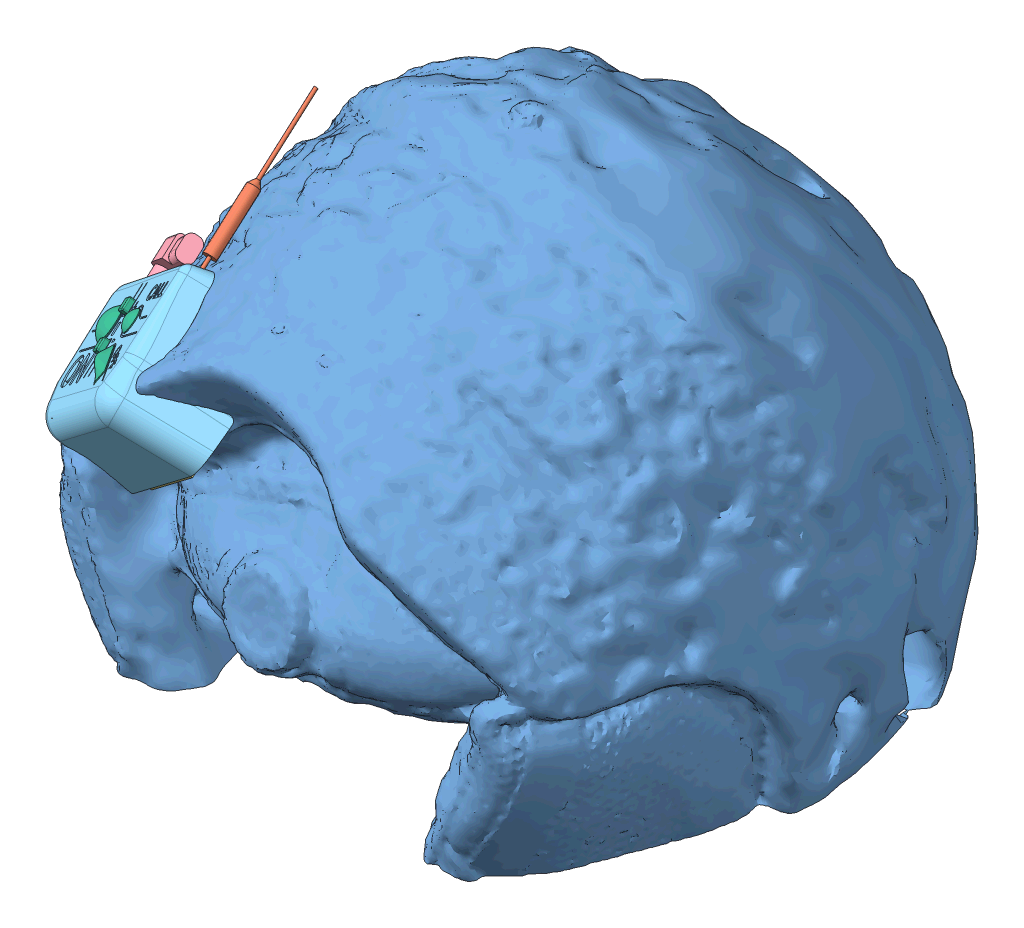
SolidWorks assembly Assem1, configuration Default. Lengths in mm.
Overall size (730.14 357.29 573.31).
6 component instances, 6 part files, 10 mates.
Components (placement in the parent):
- shield helmet-1: shield helmet [Default] at origin size (730.14 357.29 573.31)
- pcb-1: pcb [Default] at (-96.8762 130.6097 141.2413) x (-0.706127 -0.618862 -0.344083) z (0.702545 -0.551659 -0.449559) size (69.38 94.69 8.1)
- lipo850mAh30x50x6-1: lipo850mAh30x50x6 [Default] at (-104.9822 76.5067 159.1811) x (-0.702545 0.551659 0.449559) z (-0.706127 -0.618862 -0.344083) size (33 6 50)
- 3.5mmJack-1: 3.5mmJack [Default] at (-134.7323 85.3661 128.7033) x (-0.088398 0.55918 -0.82432) z (-0.749695 0.507541 0.424687) size (29.7 25 9.1)
- cover-1: cover [Default] at (-142.2057 72.0373 142.2779) x (0.706127 0.618862 0.344083) z (-0.702545 0.551659 0.449559) size (92.82 60.91 40.13)
- bumps-1: bumps [Default] at (-129.3087 97.2732 139.6956) x (0.706127 0.618862 0.344083) z (-0.702545 0.551659 0.449559) size (37.21 28.42 3.92)
Mates (geometry in assembly coordinates):
- Concentric1: concentric: cylinder of pcb-1 through (-132.8698 73.5841 146.0718) axis (-0.088398 0.55918 -0.82432) radius 1.75; cylinder of 3.5mmJack-1 through (-135.8594 92.4957 118.1932) axis (-0.088398 0.55918 -0.82432) radius 1.75
- Coincident2: coincident: plane of pcb-1 through (-132.3409 93.9237 117.2682) normal (-0.088398 0.55918 -0.82432); plane of 3.5mmJack-1 through (-135.9699 93.1947 117.1628) normal (0.088398 -0.55918 0.82432)
- Concentric2: concentric: cylinder of pcb-1 through (-142.0895 83.7014 125.9218) axis (-0.702545 0.551659 0.449559) radius 1; cylinder of cover-1 through (-146.0388 86.8024 128.449) axis (0.702545 -0.551659 -0.449559) radius 0.75
- Coincident3: coincident: plane of pcb-1 through (-96.8762 130.6097 141.2413) normal (-0.702545 0.551659 0.449559); plane of cover-1 through (-142.7921 84.253 126.3714) normal (0.702545 -0.551659 -0.449559)
- Concentric3: concentric: cylinder of pcb-1 through (-97.3394 126.1045 143.8216) axis (-0.702545 0.551659 0.449559) radius 1; cylinder of cover-1 through (-101.2886 129.2055 146.3487) axis (0.702545 -0.551659 -0.449559) radius 0.75
- Parallel2: parallel: plane of pcb-1 through (-96.8762 130.6097 141.2413) normal (-0.702545 0.551659 0.449559); plane of lipo850mAh30x50x6-1 through (-98.3976 103.6082 169.5807) normal (-0.702545 0.551659 0.449559)
- Parallel3: parallel: plane of pcb-1 through (-96.1737 130.0581 140.7918) normal (-0.088398 0.55918 -0.82432); plane of lipo850mAh30x50x6-1 through (-105.5126 79.8618 154.2352) normal (-0.088398 0.55918 -0.82432)
- Coincident4: coincident: plane of cover-1 through (-144.0052 90.8868 124.5656) normal (-0.702545 0.551659 0.449559); plane of bumps-1 through (-129.3087 97.2732 139.6956) normal (0.702545 -0.551659 -0.449559)
- Concentric4: concentric: cylinder of cover-1 through (-105.7079 78.7412 124.5935) axis (-0.702545 0.551659 0.449559) radius 6.7; cylinder of bumps-1 through (-129.5194 97.4387 139.8305) axis (0.702545 -0.551659 -0.449559) radius 6
- Parallel4: parallel: plane of cover-1 through (-142.2057 72.0373 142.2779) normal (0.706127 0.618862 0.344083); plane of bumps-1 through (-129.3087 97.2732 139.6956) normal (0.706127 0.618862 0.344083)
